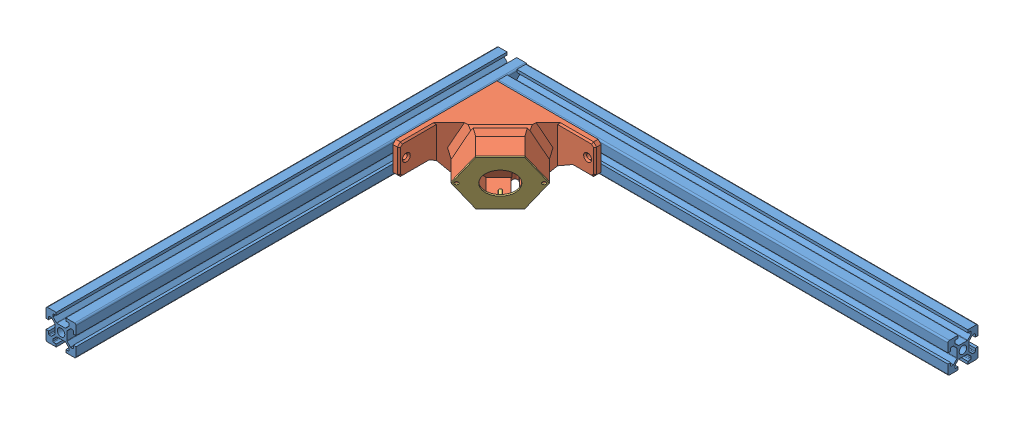
SolidWorks assembly Assem_SAVE, configuration Default. Lengths in mm.
Overall size (340.27 56.2 320.27).
4 component instances, 3 part files, 10 mates.
Components (placement in the parent):
- 2020 alu section-1: 2020 alu section [Default] at origin size (20 20 300)
- 2020 alu section-2: 2020 alu section [Default] at (320 0 0) x (0 0 1) z (-1 0 0) size (20 20 300)
- BOTTOM_C30_V3-1: BOTTOM_C30_V3 [Default] at (26.5958 -15.5558 51.7921) x (0.707107 0 -0.707107) z (-0.213483 -0.953336 -0.213483) size (98.01 54.61 41.34)
- TOP_C30_V3_G-1: TOP_C30_V3_G [Default] at (56.5621 -2.5254 54.3635) x (-0.707107 0 0.707107) z (0.213483 0.953336 0.213483) size (46.19 7 40)
Mates (geometry in assembly coordinates):
- Coincident1: coincident anti-aligned: plane of 2020 alu section-1 through (20 0 300) normal (1 0 0); plane of 2020 alu section-2 through (20 0 0) normal (-1 0 0)
- Coincident2: coincident aligned: plane of 2020 alu section-1 through (0 0 0) normal (0 0 -1); plane of 2020 alu section-2 through (20 0 0) normal (0 0 -1)
- Coincident3: coincident aligned: plane of 2020 alu section-1 through (0 20 300) normal (0 1 0); plane of 2020 alu section-2 through (20 20 0) normal (0 1 0)
- Coincident4: coincident aligned: plane of 2020 alu section-1 through (0 20 300) normal (0 1 0); plane of TESTFIT_V1-2 through (20.246 20 0.7566) normal (0 1 0)
- Coincident9: coincident anti-aligned: plane of 2020 alu section-1 through (20 0 300) normal (1 0 0); plane of BOTTOM_C30_V3-1 through (20 0 89.3051) normal (-1 0 0)
- Coincident10: coincident anti-aligned: plane of 2020 alu section-2 through (20 0 20) normal (0 0 1); plane of BOTTOM_C30_V3-1 through (20 0 20) normal (0 0 -1)
- Coincident11: coincident aligned: plane of 2020 alu section-2 through (20 20 0) normal (0 1 0); plane of BOTTOM_C30_V3-1 through (20 20 0) normal (0 1 0)
- Parallel1: parallel: plane of BOTTOM_C30_V3-1 through (38.7298 -20.9901 63.9261) normal (0.674111 -0.30191 0.674111); plane of TOP_C30_V3_G-1 through (56.5621 -2.5254 54.3635) normal (-0.674111 0.30191 -0.674111)
- Coincident15: coincident: point of BOTTOM_C30_V3-1; point of TOP_C30_V3_G-1
- Coincident16: coincident: point of BOTTOM_C30_V3-1; point of TOP_C30_V3_G-1
